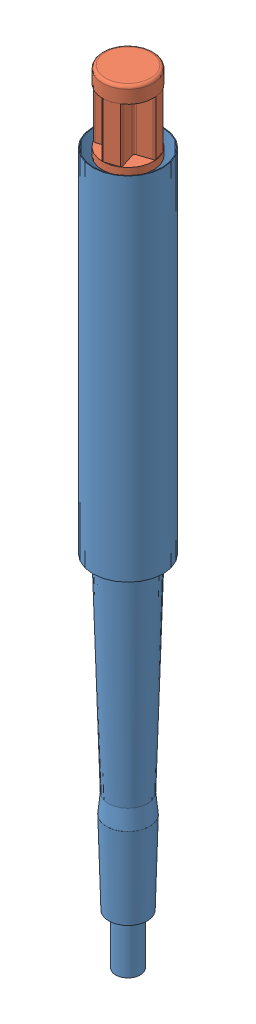
SolidWorks assembly biopsy-assembly, configuration Default. Lengths in mm.
Overall size (10.58 105.67 10.58).
2 component instances, 2 part files, 1 mates.
Components (placement in the parent):
- biopsy-body-1: biopsy-body [Default] at origin size (9.5 96.04 9.5)
- biopsy-piston-2: biopsy-piston [Default] at (0 7.4683 0) x (-0.951126 0 0.308804) z (-0.308804 0 -0.951126) size (8.4 95.11 8.4)
Mates (geometry in assembly coordinates):
- Concentric1: concentric anti-aligned: cylinder of biopsy-body-1 through (0 0 0) axis (0 -1 0) radius 4.65; circle of biopsy-piston-2
